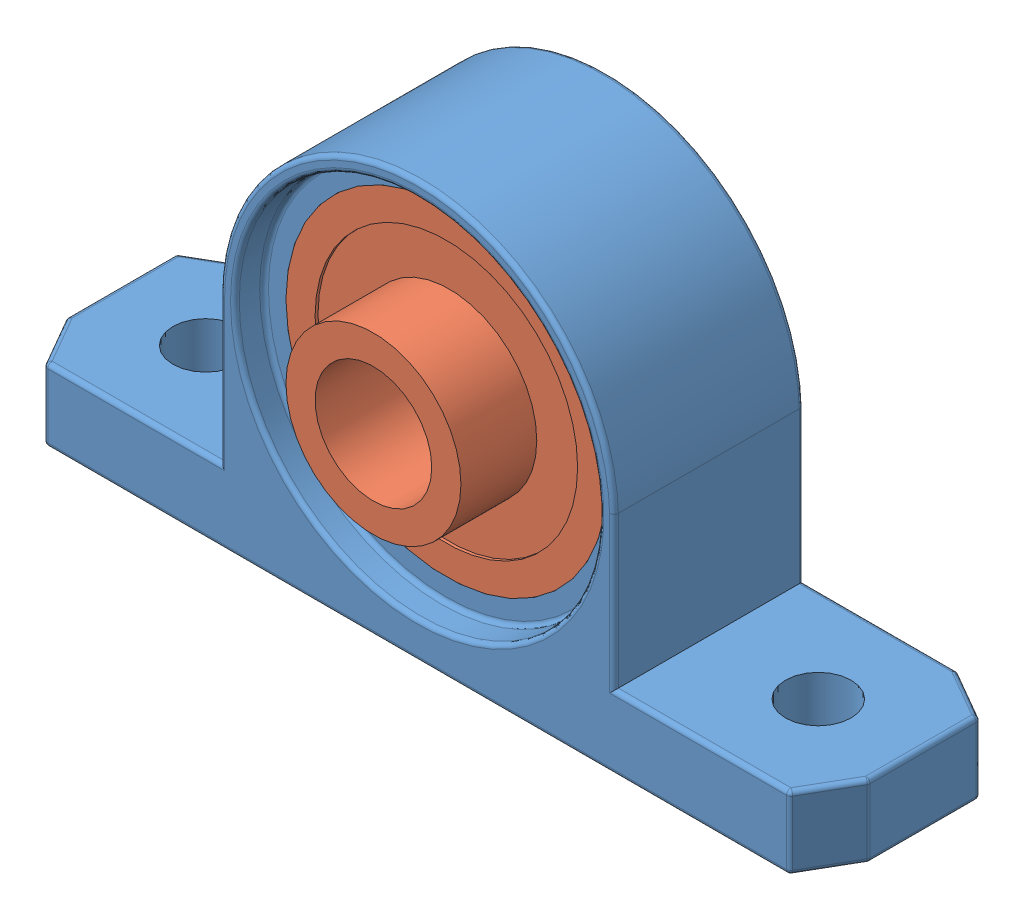
SolidWorks assembly Lagerblok_Compleet, configuration Default. Lengths in mm.
Overall size (55 28.5 16).
2 component instances, 2 part files, 1 mates.
Components (placement in the parent):
- LagerBlok-1: LagerBlok [Default] at (21.5573 21.1773 30.6055) size (55 28.5 13)
- Lager-1: Lager [Default] at (21.5573 36.1773 32.6055) size (22 22 14)
Mates (geometry in assembly coordinates):
- Coincident1: coincident aligned: circle of LagerBlok-1; circle of Lager-1
